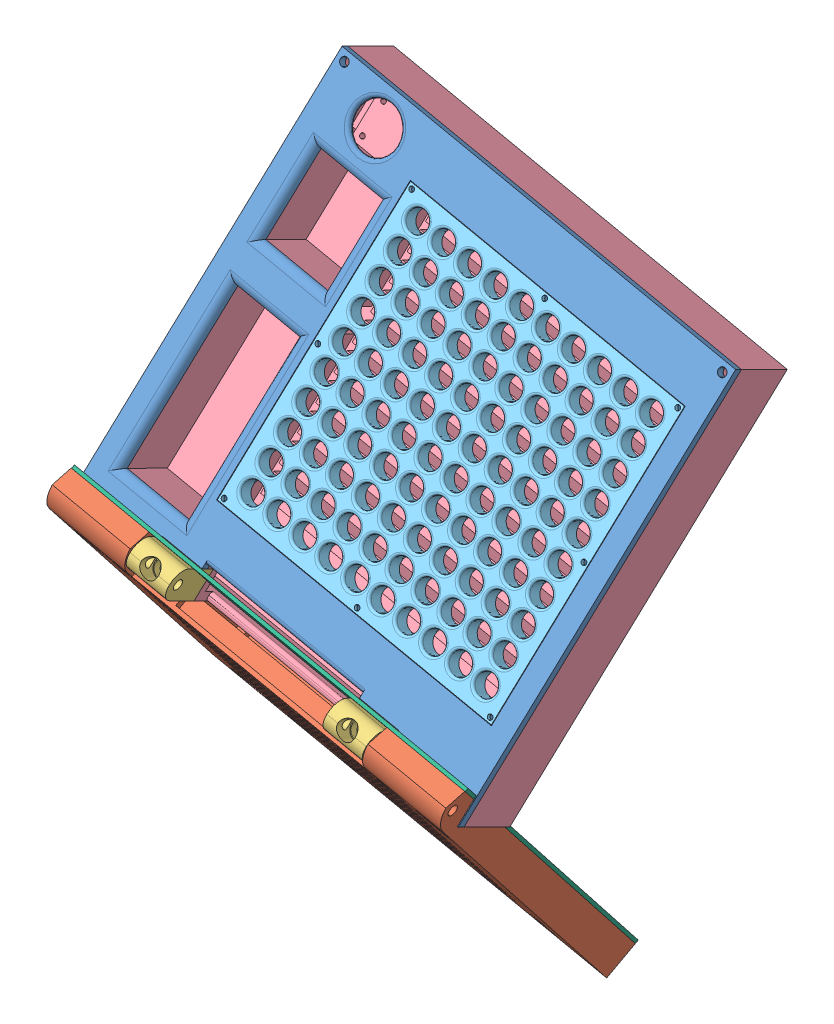
SolidWorks assembly Baugr1, configuration Standard. Lengths in mm.
Overall size (334.79 440.96 190.53).
7 component instances, 6 part files, 18 mates.
Components (placement in the parent):
- Bottom (1)-1: Bottom (1) [Standard] at (-178.8657 147.2783 177.9935) x (-0.972839 0.230577 0.020441) z (0.135286 0.494686 0.858477) size (250 250 5)
- top (1)-1: top (1) [Standard] at (-263.6818 -211.3052 210.7028) x (-0.972839 0.230577 0.020441) z (0.130235 0.6182 -0.775156) size (250 248.64 20)
- Scharnier-1: Scharnier [Standard] at (-168.4835 -39.2809 330.4538) x (-0.972839 0.230577 0.020441) z (0.187833 0.837926 -0.512444) size (25 30 17.5)
- Scharnier-2: Scharnier [Standard] at (-46.8786 -68.103 327.8987) x (-0.972839 0.230577 0.020441) z (0.187833 0.837926 -0.512444) size (25 30 17.5)
- BottomLowerPart-1: BottomLowerPart [Standard] at (-178.8657 147.2783 177.9935) x (-0.972839 0.230577 0.020441) z (0.135286 0.494686 0.858477) size (250 250 40)
- BottomHoles-1: BottomHoles [Standard] at (-178.8657 147.2783 177.9935) x (-0.972839 0.230577 0.020441) z (0.135286 0.494686 0.858477) size (174 174 10)
- topCover-1: topCover [Standard] at (-17.6068 -255.349 188.539) x (0.972839 -0.230577 -0.020441) z (-0.130235 -0.6182 0.775156) size (250 244 5)
Mates (geometry in assembly coordinates):
- Deckungsgleich3: coincident aligned: plane of Bottom (1)-1 through (-219.0597 -37.4689 349.0284) normal (-0.187833 -0.837926 0.512444); plane of Scharnier-1 through (-167.712 -39.104 365.1759) normal (-0.187833 -0.837926 0.512444)
- Deckungsgleich4: coincident anti-aligned: plane of Bottom (1)-1 through (-171.7706 -53.9446 339.4216) normal (0.972839 -0.230577 -0.020441); plane of Scharnier-1 through (-164.4249 -24.4403 356.2081) normal (-0.972839 0.230577 0.020441)
- Deckungsgleich5: coincident aligned: plane of Bottom (1)-1 through (-52.8713 -92.6604 319.6969) normal (-0.972839 0.230577 0.020441); plane of Scharnier-2 through (-42.82 -53.2624 353.653) normal (-0.972839 0.230577 0.020441)
- Deckungsgleich6: coincident aligned: plane of Bottom (1)-1 through (-219.0597 -37.4689 349.0284) normal (-0.187833 -0.837926 0.512444); plane of Scharnier-2 through (-46.1071 -67.9261 362.6208) normal (-0.187833 -0.837926 0.512444)
- Konzentrisch1: concentric aligned: cylinder of top (1)-1 through (26.9984 -81.4823 350.1754) axis (-0.972839 0.230577 0.020441) radius 3; cylinder of Scharnier-1 through (-142.7621 -41.2467 353.7424) axis (-0.972839 0.230577 0.020441) radius 3
- Konzentrisch2: concentric aligned: cylinder of top (1)-1 through (26.9984 -81.4823 350.1754) axis (-0.972839 0.230577 0.020441) radius 3; cylinder of Scharnier-2 through (-21.1572 -70.0688 351.1873) axis (-0.972839 0.230577 0.020441) radius 3
- Deckungsgleich7: coincident anti-aligned: plane of top (1)-1 through (-24.6921 -88.2217 387.7186) normal (-0.972839 0.230577 0.020441); plane of Scharnier-2 through (-18.499 -59.0268 353.142) normal (0.972839 -0.230577 -0.020441)
- LimitWinkel3: limit planar angle = 1.919862 rad anti-aligned: plane of Bottom (1)-1 through (-172.1015 172.0126 220.9174) normal (0.135286 0.494686 0.858477); plane of top (1)-1 through (-263.6818 -211.3052 210.7028) normal (-0.130235 -0.6182 0.775156)
- Concentric1: concentric aligned: cylinder of Bottom (1)-1 through (19.5487 -92.244 337.1657) axis (0.135286 0.494686 0.858477) radius 2.5; cylinder of BottomLowerPart-1 through (18.1959 -97.1908 328.581) axis (0.135286 0.494686 0.858477) radius 2.5
- Concentric2: concentric aligned: cylinder of Bottom (1)-1 through (-168.8528 164.1967 219.085) axis (0.135286 0.494686 0.858477) radius 2.5; cylinder of BottomLowerPart-1 through (-170.2057 159.2498 210.5003) axis (0.135286 0.494686 0.858477) radius 2.5
- Coincident1: coincident anti-aligned: plane of Bottom (1)-1 through (-172.7779 169.5392 216.625) normal (-0.135286 -0.494686 -0.858477); plane of BottomLowerPart-1 through (-219.7361 -39.9423 344.736) normal (0.135286 0.494686 0.858477)
- Concentric3: concentric aligned: cylinder of Bottom (1)-1 through (18.4691 -52.4987 314.4332) axis (0.135286 0.494686 0.858477) radius 1.5; cylinder of BottomHoles-1 through (18.4691 -52.4987 314.4332) axis (0.135286 0.494686 0.858477) radius 1.5
- Concentric4: concentric aligned: cylinder of Bottom (1)-1 through (-114.197 128.0783 231.2847) axis (0.135286 0.494686 0.858477) radius 1.5; cylinder of BottomHoles-1 through (-114.197 128.0783 231.2847) axis (0.135286 0.494686 0.858477) radius 1.5
- Coincident2: coincident anti-aligned: plane of Bottom (1)-1 through (-172.4397 170.7759 218.7712) normal (0.135286 0.494686 0.858477); plane of BottomHoles-1 through (-172.4397 170.7759 218.7712) normal (-0.135286 -0.494686 -0.858477)
- Coincident4: coincident anti-aligned: plane of Scharnier-1 through (-168.4835 -39.2809 330.4538) normal (-0.135286 -0.494686 -0.858477); plane of BottomLowerPart-1 through (-173.4543 167.0657 212.3326) normal (0.135286 0.494686 0.858477)
- Konzentrisch3: concentric anti-aligned: cylinder of top (1)-1 through (18.9474 -93.377 345.7869) axis (0.130235 0.6182 -0.775156) radius 2.5; cylinder of topCover-1 through (21.1613 -82.8676 332.6092) axis (-0.130235 -0.6182 0.775156) radius 2.5
- Konzentrisch4: concentric anti-aligned: cylinder of top (1)-1 through (-257.2096 -205.6099 209.882) axis (0.130235 0.6182 -0.775156) radius 2.5; cylinder of topCover-1 through (-254.9956 -195.1005 196.7043) axis (-0.130235 -0.6182 0.775156) radius 2.5
- Deckungsgleich8: coincident anti-aligned: plane of top (1)-1; plane of topCover-1
